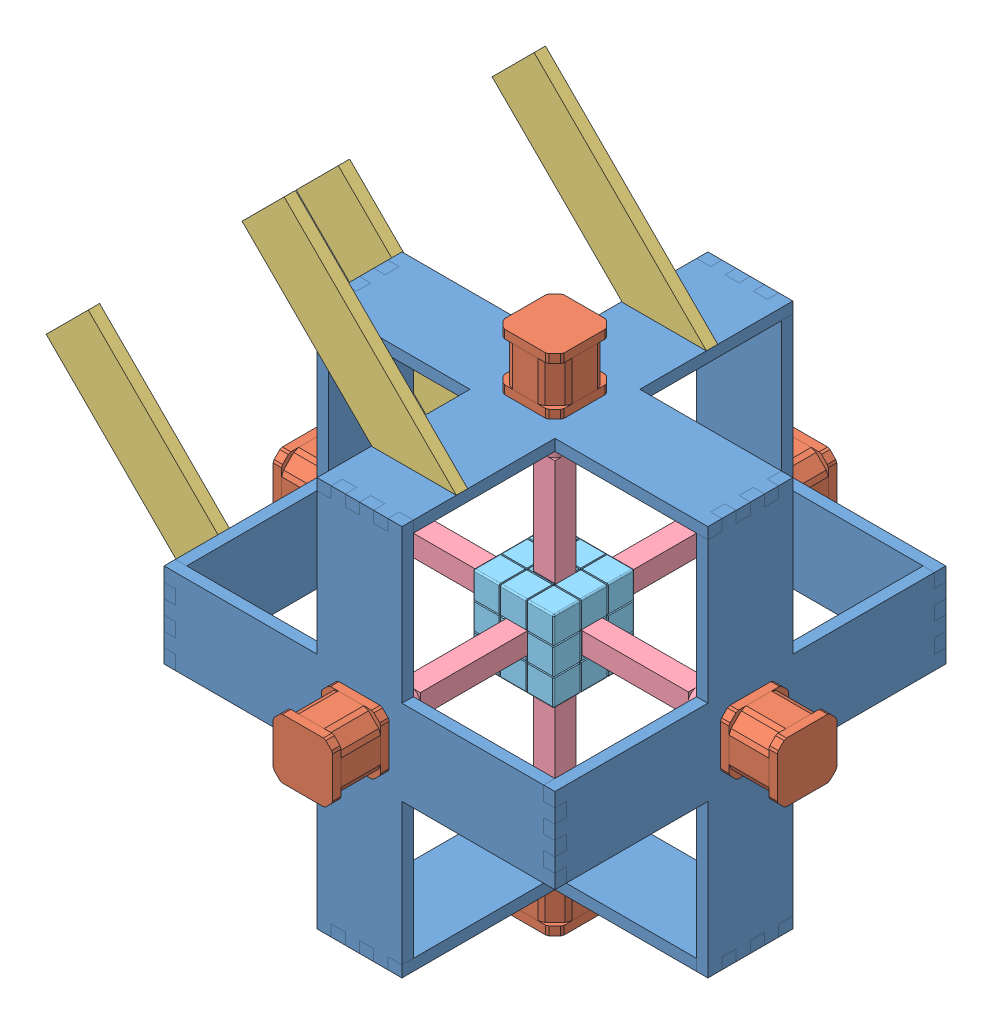
SolidWorks assembly cube装配体, configuration 默认. Lengths in mm.
Overall size (437.62 437.62 356).
23 component instances, 5 part files, 55 mates.
Components (placement in the parent):
- 固定板-3: 固定板 [默认] at (-631.6582 43.3064 202.8613) x (0 1 0) z (0 0 1) size (276 8 276)
- 42BYG_Stepper_Motor-3: 42BYG_Stepper_Motor [默认] at (-673.6582 22.3064 223.8613) x (0 1 0) z (0 0 1) size (42 64 42)
- 固定板-4: 固定板 [默认] at (-501.6582 173.3064 202.8613) size (276 8 276)
- 42BYG_Stepper_Motor-4: 42BYG_Stepper_Motor [默认] at (-522.6582 215.3064 223.8613) size (42 64 42)
- 固定板-5: 固定板 [默认] at (-501.6582 43.3064 72.8613) x (0 -1 0) z (1 0 0) size (276 8 276)
- 固定板-6: 固定板 [默认] at (-501.6582 43.3064 332.8613) x (1 0 0) z (0 -1 0) size (276 8 276)
- 固定板-7: 固定板 [默认] at (-371.6582 43.3064 202.8613) x (0 -1 0) z (0 0 1) size (276 8 276)
- 固定板-8: 固定板 [默认] at (-501.6582 -86.6936 202.8613) x (-1 0 0) z (0 0 1) size (276 8 276)
- 42BYG_Stepper_Motor-5: 42BYG_Stepper_Motor [默认] at (-522.6582 -128.6936 223.8613) x (0 0 -1) z (-1 0 0) size (42 64 42)
- 42BYG_Stepper_Motor-6: 42BYG_Stepper_Motor [默认] at (-329.6582 64.3064 223.8613) x (0 -1 0) z (0 0 1) size (42 64 42)
- 42BYG_Stepper_Motor-7: 42BYG_Stepper_Motor [默认] at (-522.6582 22.3064 30.8613) x (0 1 0) z (-1 0 0) size (42 64 42)
- 42BYG_Stepper_Motor-8: 42BYG_Stepper_Motor [默认] at (-522.6582 22.3064 374.8613) x (1 0 0) z (0 -1 0) size (42 64 42)
- 支架-1: 支架 [默认] at (-669.3567 43.0049 125.8959) x (0.707107 0.707107 0) z (-0.707107 0.707107 0) size (42 8 172)
- 支架-2: 支架 [默认] at (-501.3567 211.0049 117.8959) x (-0.707107 -0.707107 0) z (-0.707107 0.707107 0) size (42 8 172)
- 支架-3: 支架 [默认] at (-501.3567 211.0049 294.4584) x (-0.707107 -0.707107 0) z (-0.707107 0.707107 0) size (42 8 172)
- 支架-4: 支架 [默认] at (-669.3567 43.0049 302.4584) x (0.707107 0.707107 0) z (-0.707107 0.707107 0) size (42 8 172)
- 连接柱-1: 连接柱 [默认] at (-501.6582 43.3064 98.4006) x (1 0 0) z (0 1 0) size (16 102 16)
- 连接柱-2: 连接柱 [默认] at (-399.9655 43.3064 202.8613) x (0 -1 0) z (0 0 1) size (16 102 16)
- 连接柱-3: 连接柱 [默认] at (-501.6582 145.0354 202.8613) size (16 102 16)
- 连接柱-4: 连接柱 [默认] at (-606.9655 43.3064 202.8613) x (0 1 0) z (0 0 1) size (16 102 16)
- 连接柱-5: 连接柱 [默认] at (-501.6582 43.3064 305.4006) x (1 0 0) z (0 -1 0) size (16 102 16)
- 连接柱-6: 连接柱 [默认] at (-501.6582 -61.9646 202.8613) x (0 0 1) z (1 0 0) size (16 102 16)
- 魔方-1: 魔方 [默认] at (-531.9655 13.0354 173.4006) x (0 0 1) z (-1 0 0) size (57 57 57)
Mates (geometry in assembly coordinates):
- 同心4: concentric anti-aligned: circle of 固定板-3; circle of 42BYG_Stepper_Motor-3
- 同心5: concentric anti-aligned: circle of 固定板-3; circle of 42BYG_Stepper_Motor-3
- 重合12: coincident anti-aligned: plane of 固定板-3 through (-639.6582 43.3064 202.8613) normal (-1 0 0); plane of 42BYG_Stepper_Motor-3 through (-639.6582 22.3064 223.8613) normal (1 0 0)
- 同心6: concentric anti-aligned: circle of 固定板-4; circle of 42BYG_Stepper_Motor-4
- 同心7: concentric anti-aligned: circle of 固定板-4; circle of 42BYG_Stepper_Motor-4
- 重合14: coincident anti-aligned: plane of 固定板-4 through (-501.6582 181.3064 202.8613) normal (0 1 0); plane of 42BYG_Stepper_Motor-4 through (-522.6582 181.3064 223.8613) normal (0 -1 0)
- 重合18: coincident aligned: plane of 固定板-3 through (-639.6582 181.3064 192.8613) normal (0 1 0); plane of 固定板-4 through (-501.6582 181.3064 202.8613) normal (0 1 0)
- 重合19: coincident aligned: plane of 固定板-3 through (-639.6582 73.3064 172.8613) normal (0 0 -1); plane of 固定板-4 through (-639.6582 181.3064 172.8613) normal (0 0 -1)
- 重合20: coincident aligned: plane of 固定板-3 through (-639.6582 43.3064 202.8613) normal (-1 0 0); plane of 固定板-4 through (-639.6582 181.3064 182.8613) normal (-1 0 0)
- 重合21: coincident aligned: plane of 固定板-3 through (-639.6582 43.3064 64.8613) normal (0 0 -1); plane of 固定板-5 through (-501.6582 43.3064 64.8613) normal (0 0 -1)
- 重合22: coincident aligned: plane of 固定板-3 through (-639.6582 43.3064 202.8613) normal (-1 0 0); plane of 固定板-5 through (-639.6582 23.3064 64.8613) normal (-1 0 0)
- 重合23: coincident aligned: plane of 固定板-3 through (-639.6582 13.3064 172.8613) normal (0 -1 0); plane of 固定板-5 through (-531.6582 13.3064 64.8613) normal (0 -1 0)
- 重合24: coincident aligned: plane of 固定板-4 through (-501.6582 181.3064 202.8613) normal (0 1 0); plane of 固定板-6 through (-501.6582 181.3064 340.8613) normal (0 1 0)
- 重合25: coincident aligned: plane of 固定板-4 through (-471.6582 181.3064 332.8613) normal (1 0 0); plane of 固定板-6 through (-471.6582 73.3064 340.8613) normal (1 0 0)
- 重合26: coincident anti-aligned: plane of 固定板-4 through (-481.6582 181.3064 332.8613) normal (0 0 1); plane of 固定板-6 through (-501.6582 43.3064 332.8613) normal (0 0 -1)
- 重合27: coincident anti-aligned: plane of 固定板-4 through (-371.6582 181.3064 192.8613) normal (1 0 0); plane of 固定板-7 through (-371.6582 43.3064 202.8613) normal (-1 0 0)
- 重合28: coincident aligned: plane of 固定板-4 through (-471.6582 181.3064 172.8613) normal (0 0 -1); plane of 固定板-7 through (-363.6582 181.3064 172.8613) normal (0 0 -1)
- 重合29: coincident anti-aligned: plane of 固定板-4 through (-501.6582 173.3064 202.8613) normal (0 -1 0); plane of 固定板-7 through (-363.6582 173.3064 192.8613) normal (0 1 0)
- 重合30: coincident anti-aligned: plane of 固定板-7 through (-363.6582 -86.6936 172.8613) normal (0 -1 0); plane of 固定板-8 through (-501.6582 -86.6936 202.8613) normal (0 1 0)
- 重合31: coincident aligned: plane of 固定板-7 through (-363.6582 13.3064 232.8613) normal (0 0 1); plane of 固定板-8 through (-371.6582 -94.6936 232.8613) normal (0 0 1)
- 重合32: coincident aligned: plane of 固定板-7 through (-363.6582 43.3064 202.8613) normal (1 0 0); plane of 固定板-8 through (-363.6582 -94.6936 182.8613) normal (1 0 0)
- 同心8: concentric anti-aligned: circle of 固定板-6; circle of 42BYG_Stepper_Motor-8
- 同心9: concentric anti-aligned: circle of 固定板-6; circle of 42BYG_Stepper_Motor-8
- 重合34: coincident anti-aligned: plane of 固定板-6 through (-501.6582 43.3064 340.8613) normal (0 0 1); plane of 42BYG_Stepper_Motor-8 through (-522.6582 22.3064 340.8613) normal (0 0 -1)
- 同心10: concentric anti-aligned: circle of 固定板-7; circle of 42BYG_Stepper_Motor-6
- 同心11: concentric anti-aligned: circle of 固定板-7; circle of 42BYG_Stepper_Motor-6
- 重合36: coincident anti-aligned: plane of 固定板-7 through (-363.6582 43.3064 202.8613) normal (1 0 0); plane of 42BYG_Stepper_Motor-6 through (-363.6582 64.3064 223.8613) normal (-1 0 0)
- 同心12: concentric anti-aligned: circle of 固定板-8; circle of 42BYG_Stepper_Motor-5
- 同心13: concentric anti-aligned: circle of 固定板-8; circle of 42BYG_Stepper_Motor-5
- 重合39: coincident anti-aligned: plane of 固定板-8 through (-501.6582 -94.6936 202.8613) normal (0 -1 0); plane of 42BYG_Stepper_Motor-5 through (-522.6582 -94.6936 223.8613) normal (0 1 0)
- 同心14: concentric anti-aligned: circle of 固定板-5; circle of 42BYG_Stepper_Motor-7
- 同心15: concentric anti-aligned: circle of 固定板-5; circle of 42BYG_Stepper_Motor-7
- 重合41: coincident anti-aligned: plane of 固定板-5 through (-501.6582 43.3064 64.8613) normal (0 0 -1); plane of 42BYG_Stepper_Motor-7 through (-522.6582 22.3064 64.8613) normal (0 0 1)
- 重合42: coincident anti-aligned: plane of 固定板-4 through (-501.6582 181.3064 202.8613) normal (0 1 0); plane of 支架-2 through (-471.6582 181.3064 125.8959) normal (0 -1 0)
- 重合43: coincident aligned: line of 固定板-4 through (-471.6582 181.3064 172.8613) axis (0 0 -1); line of 支架-2 through (-471.6582 181.3064 125.8959) axis (0 0 -1)
- 重合44: coincident anti-aligned: plane of 固定板-4 through (-501.6582 181.3064 202.8613) normal (0 1 0); plane of 支架-3 through (-471.6582 181.3064 302.4584) normal (0 -1 0)
- 重合45: coincident aligned: line of 固定板-4 through (-471.6582 181.3064 332.8613) axis (0 0 -1); line of 支架-3 through (-471.6582 181.3064 302.4584) axis (0 0 -1)
- 重合46: coincident anti-aligned: plane of 固定板-3 through (-639.6582 43.3064 202.8613) normal (-1 0 0); plane of 支架-1 through (-639.6582 13.3064 117.8959) normal (1 0 0)
- 重合47: coincident aligned: line of 固定板-3 through (-639.6582 13.3064 232.8613) axis (0 0 1); line of 支架-1 through (-639.6582 13.3064 117.8959) axis (0 0 1)
- 重合48: coincident anti-aligned: plane of 固定板-3 through (-639.6582 43.3064 202.8613) normal (-1 0 0); plane of 支架-4 through (-639.6582 13.3064 294.4584) normal (1 0 0)
- 重合49: coincident aligned: line of 固定板-3 through (-639.6582 13.3064 72.8613) axis (0 0 1); line of 支架-4 through (-639.6582 13.3064 294.4584) axis (0 0 1)
- 同心16: concentric aligned: cylinder of 42BYG_Stepper_Motor-5 through (-501.6582 -70.6936 202.8613) axis (0 -1 0) radius 2; cylinder of 连接柱-6 through (-501.6582 -72.9646 202.8613) axis (0 -1 0) radius 2
- 同心17: concentric aligned: cylinder of 42BYG_Stepper_Motor-4 through (-501.6582 157.3064 202.8613) axis (0 1 0) radius 2; cylinder of 连接柱-3 through (-501.6582 156.0354 202.8613) axis (0 1 0) radius 2
- 同心18: concentric aligned: cylinder of 42BYG_Stepper_Motor-3 through (-615.6582 43.3064 202.8613) axis (-1 0 0) radius 2; cylinder of 连接柱-4 through (-617.9655 43.3064 202.8613) axis (-1 0 0) radius 2
- 同心19: concentric aligned: cylinder of 42BYG_Stepper_Motor-7 through (-501.6582 43.3064 88.8613) axis (0 0 -1) radius 2; cylinder of 连接柱-1 through (-501.6582 43.3064 87.4006) axis (0 0 -1) radius 2
- 同心20: concentric aligned: cylinder of 42BYG_Stepper_Motor-8 through (-501.6582 43.3064 316.8613) axis (0 0 1) radius 2; cylinder of 连接柱-5 through (-501.6582 43.3064 316.4006) axis (0 0 1) radius 2
- 同心21: concentric aligned: cylinder of 42BYG_Stepper_Motor-6 through (-387.6582 43.3064 202.8613) axis (1 0 0) radius 2; cylinder of 连接柱-2 through (-388.9655 43.3064 202.8613) axis (1 0 0) radius 2
- 重合53: coincident anti-aligned: plane of 连接柱-1 through (-501.6582 43.3064 178.4006) normal (0 0 1); plane of 魔方-1 through (-531.9655 13.0354 178.4006) normal (0 0 -1)
- 重合55: coincident anti-aligned: plane of 连接柱-6 through (-501.6582 18.0354 202.8613) normal (0 1 0); plane of 魔方-1 through (-531.9655 18.0354 173.4006) normal (0 -1 0)
- 重合56: coincident anti-aligned: plane of 连接柱-2 through (-479.9655 43.3064 202.8613) normal (-1 0 0); plane of 魔方-1 through (-479.9655 13.0354 173.4006) normal (1 0 0)
- 重合57: coincident anti-aligned: plane of 连接柱-3 through (-501.6582 65.0354 202.8613) normal (0 -1 0); plane of 魔方-1 through (-531.9655 65.0354 173.4006) normal (0 1 0)
- 重合58: coincident anti-aligned: plane of 连接柱-4 through (-526.9655 43.3064 202.8613) normal (1 0 0); plane of 魔方-1 through (-526.9655 13.0354 173.4006) normal (-1 0 0)
- 重合59: coincident anti-aligned: plane of 连接柱-5 through (-501.6582 43.3064 225.4006) normal (0 0 -1); plane of 魔方-1 through (-531.9655 13.0354 225.4006) normal (0 0 1)
- 重合61: coincident aligned: plane of 支架-1 through (-669.3567 43.0049 117.8959) normal (0 0 -1); plane of 支架-2 through (-501.3567 211.0049 117.8959) normal (0 0 -1)
- 重合62: coincident aligned: plane of 支架-3 through (-501.3567 211.0049 302.4584) normal (0 0 1); plane of 支架-4 through (-669.3567 43.0049 302.4584) normal (0 0 1)
